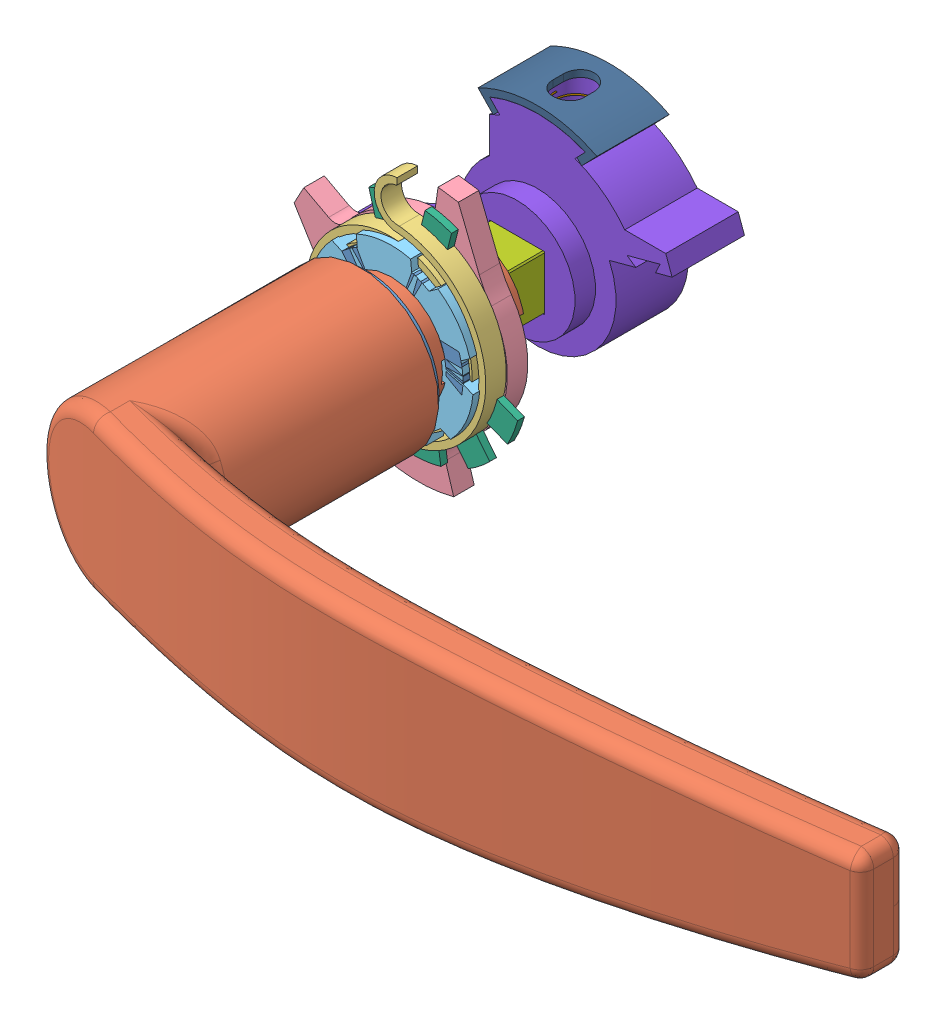
SolidWorks assembly poignee interieure, configuration Défaut. Lengths in mm.
Overall size (141.17 41.55 90.38).
12 component instances, 10 part files, 16 mates.
Components (placement in the parent):
- pièce a3-1: pièce a3 [Défaut] at (-71.1604 -5.4234 32) size (21 21 1)
- bequille-1: bequille [Défaut] at (-71.0969 -5.4234 32.5) x (0 -1 0) z (0 0 -1) size (41.55 120 69.88)
- pièce a5-1: pièce a5 [Défaut] at (-71.9888 -5.5153 25.5) x (0.053548 -0.998565 0) z (0 0 1) size (33.22 26.47 3.09)
- pièce a16-1: pièce a16 [Défaut] at (-71.1604 -5.4234 24) x (-0.999972 -0.007518 0) z (0 0 -1) size (31.16 38.76 3.06)
- pièce a4-1: pièce a4 [Défaut] at (-71.1604 -5.4234 28) x (0.409792 0.912179 0) z (0 0 -1) size (23.6 24 3)
- pièce a7bis-1: pièce a7bis [Défaut] at (-71.1604 -5.4234 25) x (-0.96958 0.244776 0) z (0 0 -1) size (28 32 1)
- pièce a3-2: pièce a3 [Défaut] at (-71.1604 -5.4234 27.5) size (21 21 1)
- carre-1: carre [Défaut] at (-71.1604 -5.4234 51.5) size (8 8 52)
- Assemblage4-1: Assemblage4 [Défaut] at (-71.1604 -5.4234 1.3) size (52.31 35.86 13.6)
  - Pièce14-1: Pièce14 [Défaut] at origin size (52.31 34.86 13.6)
  - ressort1-1: ressort1 [Défaut] at (0 11 0) x (-0.996138 0 -0.087798) z (0 1 0) size (5.8 6.7 9.79)
  - Pièce15-1: Pièce15 [Défaut] at origin size (17.38 4.41 10.6)
Mates (geometry in assembly coordinates):
- Coïncidente28: coincident anti-aligned: plane of pièce a3-1 through (-71.1604 -5.4234 32.5) normal (0 0 1); plane of bequille-1 through (-71.1604 -5.4234 32.5) normal (0 0 -1)
- Coaxiale18: concentric aligned: cylinder of bequille-1 through (-71.1604 -5.4234 16.5) axis (0 0 1) radius 8; cylinder of pièce a16-1 through (-71.1604 -5.4234 21) axis (0 0 1) radius 8
- Coïncidente44: coincident: plane of bequille-1 through (-91.1604 -6.9234 28.5) normal (0 1 0); line of pièce a5-1 through (-79.5725 -6.9234 24) axis (0 0 1)
- Coïncidente47: coincident: plane of bequille-1 through (-91.1604 -6.9234 28.5) normal (0 1 0); line of pièce a5-1 through (-79.5725 -6.9234 24) axis (0 0 1)
- Coïncidente48: coincident anti-aligned: plane of pièce a5-1 through (-80.6485 -5.9797 24) normal (0 0 -1); plane of pièce a16-1 through (-71.1604 -5.4234 24) normal (0 0 1)
- Coaxiale11: concentric anti-aligned: cylinder of pièce a4-1 through (-71.1604 -5.4234 25) axis (0 0 -1) radius 7; cylinder of bequille-1 through (-71.1604 -5.4234 16.5) axis (0 0 1) radius 8
- Coaxiale19: concentric aligned: cylinder of bequille-1 through (-71.1604 -5.4234 16.5) axis (0 0 1) radius 8; cylinder of pièce a7bis-1 through (-71.1604 -5.4234 24) axis (0 0 1) radius 8
- Coïncidente39: coincident anti-aligned: plane of bequille-1 through (-91.1604 -6.9234 28.5) normal (0 1 0); plane of pièce a7bis-1 through (-75.6604 -6.9234 24) normal (0 -1 0)
- Coïncidente17: coincident aligned: plane of pièce a5-1 through (-80.6485 -5.9797 24) normal (0 0 -1); plane of pièce a7bis-1 through (-71.3343 6.5221 24) normal (0 0 -1)
- Coïncidente38: coincident aligned: plane of pièce a5-1 through (-80.6485 -5.9797 24) normal (0 0 -1); plane of pièce a7bis-1 through (-71.3343 6.5221 24) normal (0 0 -1)
- Coïncidente19: coincident anti-aligned: plane of pièce a4-1 through (-71.1604 -5.4234 25) normal (0 0 -1); plane of pièce a7bis-1 through (-71.3343 6.5221 25) normal (0 0 1)
- Coaxiale4: concentric anti-aligned: cylinder of pièce a3-2 through (-71.1604 -5.4234 28) axis (0 0 -1) radius 8; cylinder of bequille-1 through (-71.1604 -5.4234 16.5) axis (0 0 1) radius 8
- Coïncidente46: coincident anti-aligned: plane of pièce a3-2 through (-71.1604 -5.4234 27) normal (0 0 -1); plane of pièce a5-1 through (-79.65 -5.9262 27) normal (0 0 1)
- Coïncidente49: coincident anti-aligned: plane of carre-1 through (-75.1604 -1.4234 -0.5) normal (0 1 0); plane of bequille-1 through (-75.1604 -1.4234 51.5) normal (0 -1 0)
- Coïncidente50: coincident anti-aligned: plane of bequille-1 through (-67.1604 -1.4234 51.5) normal (-1 0 0); plane of carre-1 through (-67.1604 -1.4234 -0.5) normal (1 0 0)
- Coïncidente51: coincident anti-aligned: plane of bequille-1 through (-75.1604 -1.4234 51.5) normal (0 0 -1); plane of carre-1 through (-75.1604 -9.4234 51.5) normal (0 0 1)
